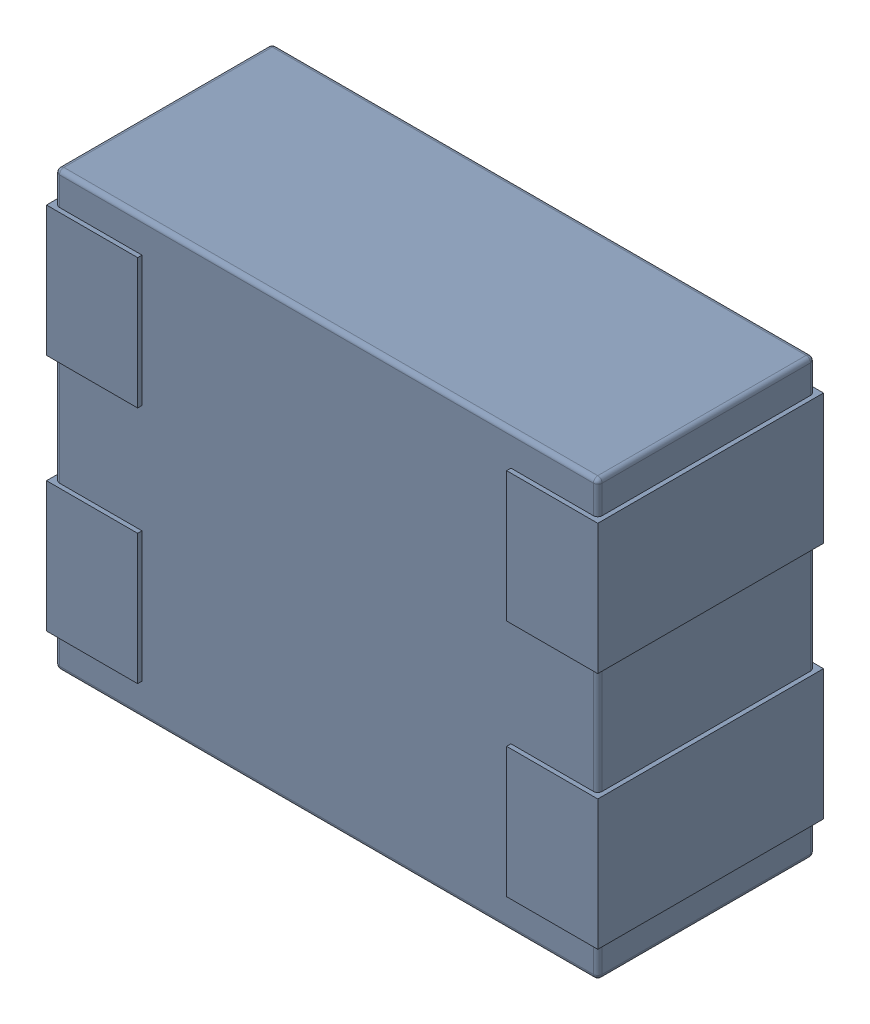
SolidWorks assembly L16, configuration Défaut. Lengths in mm.
Overall size (1.27 1 0.52).
4 component instances, 1 part files, 0 mates.
Components (placement in the parent):
- MCZ1210DH900L2TA0G-1: MCZ1210DH900L2TA0G [Défaut] at (76.7165 -24.4725 -1.6) x (0 -1 0) z (0 0 1) size (1 1.27 0.52)
  - 3D_PCB1_2021-12-30 (1).step-1: 3D_PCB1_2021-12-30 (1).step [Défaut] at origin size (1 1.27 0.52)
    - a3ec64f90eb5404ebd79eca0046a794a.step-1: a3ec64f90eb5404ebd79eca0046a794a.step [Défaut] at (5.0419 -6.8961 1.6) size (1 1.27 0.52)
      - SOLID.step_650-1: SOLID.step_650 [Défaut] at origin size (1 1.27 0.52)
